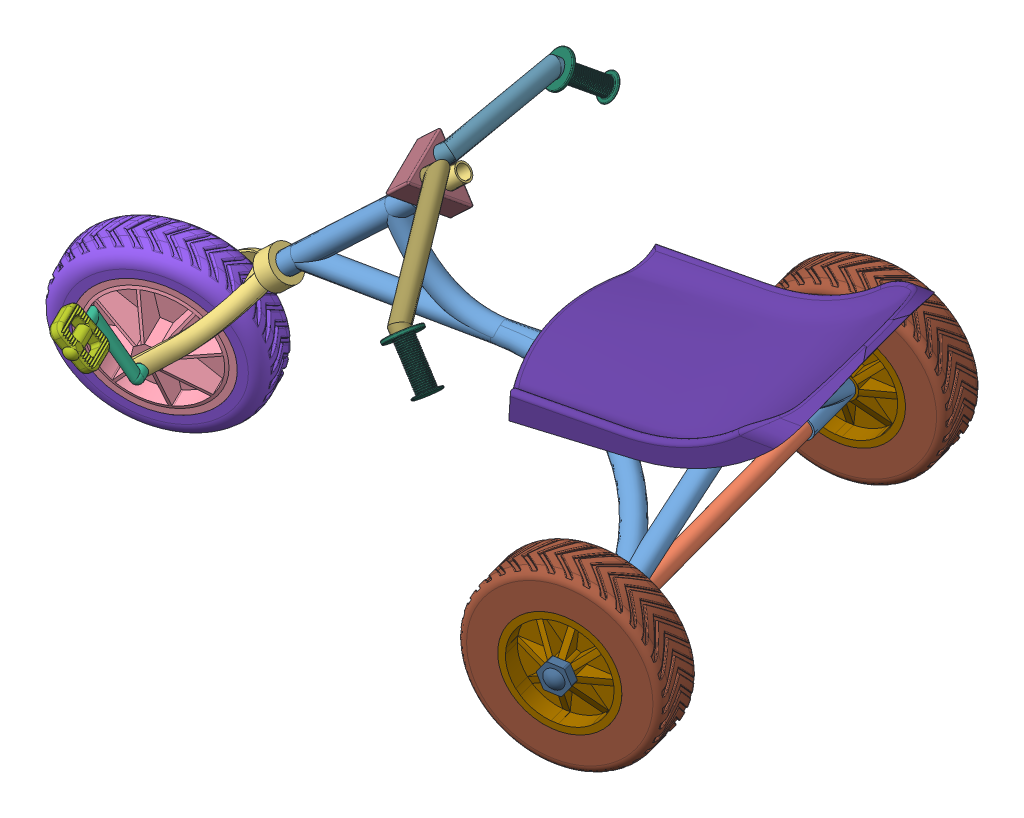
SolidWorks assembly Fiets, configuration Default. Lengths in mm.
Overall size (906.09 547.68 611.83).
25 component instances, 17 part files, 32 mates.
Components (placement in the parent):
- frame-1: frame [Default] at (642.1584 25.2869 3346.6526) x (-0.963262 0.054035 0.263071) z (-0.263456 0 -0.964672) size (454.25 227.22 420.33)
- Achteras-1: Achteras [Default] at (663.0616 75 3631.1981) x (0.960491 -0.092999 -0.262314) z (-0.263456 0 -0.964672) size (20.04 20.01 560.04)
- voorvork+wiel+band-1: voorvork+wiel+band [Default] at (-75.4458 234.9632 3697.8312) x (-0.379608 0.139583 -0.914557) z (0.583431 -0.731077 -0.353745) size (248 508.91 250.19)
  - voorvork-1: voorvork [Default] at (100.9229 178.2623 269.7183) size (130.11 396.12 40)
  - wiel-1: wiel [Default] at (100.9229 44.4443 269.7183) x (0 0.200278 -0.979739) z (1 0 0) size (179.66 179.66 90.02)
  - vooras-1: vooras [Default] at (140.9229 44.4443 269.7183) x (0 -0.74834 -0.663315) z (-1 0 0) size (13.86 12 140)
  - trapper1-3: trapper1 [Default] at (160.9229 44.4443 269.7183) x (0 -0.200278 0.979739) z (0 0.979739 0.200278) size (83 60 14)
  - trapper1-4: trapper1 [Default] at (40.9229 44.4443 269.7183) x (0 0.200278 -0.979739) z (0 0.979739 0.200278) size (83 60 14)
  - trapper2-1: trapper2 [Default] at (20.9229 57.9534 207.1148) x (0 0.085065 -0.996375) z (1 0 0) size (55 15.8 44)
  - trapper2-2: trapper2 [Default] at (180.9229 36.0058 336.0969) x (0 -0.930146 0.36719) z (-1 0 0) size (55 15.8 44)
  - voorband-1: voorband [Default] at (70.9229 44.4443 269.7183) x (0 0.189897 0.981804) z (1 0 0) size (213.53 213.53 60)
- achterwiel-1: achterwiel [Default] at (533.9684 75 3158.509) x (-0.615733 0.769802 0.168159) z (-0.263456 0 -0.964672) size (150 150 60)
- achterwiel-2: achterwiel [Default] at (660.427 75 3621.5514) x (-0.089713 -0.995666 0.024501) z (-0.263456 0 -0.964672) size (150 150 60)
- bout-achteras-1: bout-achteras [Default] at (663.0616 75 3631.1981) x (0.960491 -0.092999 -0.262314) z (-0.263456 0 -0.964672) size (34.02 30 15.01)
- bout-achteras-2: bout-achteras [Default] at (515.5265 75 3090.982) x (-0.960491 0.092999 0.262314) z (0.263456 0 0.964672) size (34.02 30 15.01)
- Achterband-1: Achterband [Default] at (644.6197 75 3563.6711) x (0.960491 -0.092999 -0.262314) z (0.263456 0 0.964672) size (201.31 201.31 60)
- Achterband-2: Achterband [Default] at (518.161 75 3100.6288) x (-0.960491 0.092999 0.262314) z (0.263456 0 0.964672) size (201.31 201.31 60)
- stuur-1: stuur [Default] at (294.7106 365.6419 3434.6157) x (-0.379608 0.139583 -0.914557) z (0.583431 -0.731077 -0.353745) size (435.74 60.06 120.1)
  - stuurbuis1-2: stuurbuis1 [Default] at (-32.5291 -26.394 40.1826) x (-0.965926 0 0.258819) z (-0.258819 0 -0.965926) size (215.96 50 55.96)
  - stuur-tussenstuk-1: stuur-tussenstuk [Default] at (-17.5291 -26.394 90.1345) size (72.07 30.12 62.95)
  - stuurbuis2-1: stuurbuis2 [Default] at (-2.5291 -26.394 40.1826) x (0.965926 0 0.258819) z (-0.258819 0 0.965926) size (215.96 50 55.96)
  - handvat-1: handvat [Default] at (-189.5772 13.606 85.9238) x (-0.5 0 0.866025) z (-0.866025 0 -0.5) size (57 40 40)
  - handvat-2: handvat [Default] at (154.5191 13.606 85.9238) x (0.5 0 0.866025) z (-0.866025 0 0.5) size (57 40 40)
- stuurpen-1: stuurpen [Default] at (319.6176 316.8448 3417.7204) x (0.424318 0.904714 -0.038042) z (0.822102 -0.402505 -0.402664) size (10 33.43 10)
- stoel-1: stoel [Default] at (397.4291 243.1345 3283.9169) x (0.263456 0 0.964672) z (-0.963262 0.054035 0.263071) size (270.97 155.75 335.98)
Mates (geometry in assembly coordinates):
- Coincident2: coincident anti-aligned: circle of frame-1; cylinder of Achteras-1 through (515.5265 75 3090.982) axis (0.263456 0 0.964672) radius 10
- Coincident4: coincident anti-aligned: circle of frame-1; circle of voorvork+wiel+band-1/voorvork-1
- Concentric2: concentric anti-aligned: circle of frame-1; circle of achterwiel-1
- Coincident5: coincident aligned: circle of frame-1; plane of achterwiel-1 through (533.9684 75 3158.509) normal (0.263456 0 0.964672)
- Concentric3: concentric aligned: cylinder of Achteras-1 through (515.5265 75 3090.982) axis (0.263456 0 0.964672) radius 10; cylinder of achterwiel-2 through (652.5234 75 3592.6112) axis (0.263456 0 0.964672) radius 10
- Coincident7: coincident anti-aligned: circle of frame-1; plane of achterwiel-2 through (644.6197 75 3563.6711) normal (-0.263456 0 -0.964672)
- Tangent3: tangent anti-aligned: cylinder of achterwiel-1 through (526.0647 75 3129.5689) axis (0.263456 0 0.964672) radius 75; plane of assembly through (0 0 0) normal (0 1 0)
- Distance1: distance = 70 mm anti-aligned: plane of Achteras-1 through (515.5265 75 3090.982) normal (-0.263456 0 -0.964672); plane of achterwiel-1 through (533.9684 75 3158.509) normal (0.263456 0 0.964672)
- Concentric4: concentric anti-aligned: cylinder of Achteras-1 through (515.5265 75 3090.982) axis (0.263456 0 0.964672) radius 10; circle of bout-achteras-1
- Coincident14: coincident anti-aligned: plane of achterwiel-2 through (660.427 75 3621.5514) normal (0.263456 0 0.964672); plane of bout-achteras-1 through (660.427 75 3621.5514) normal (-0.263456 0 -0.964672)
- Coincident15: coincident aligned: cylinder of Achteras-1 through (515.5265 75 3090.982) axis (0.263456 0 0.964672) radius 10; circle of bout-achteras-2
- Coincident16: coincident anti-aligned: plane of achterwiel-1 through (518.161 75 3100.6288) normal (-0.263456 0 -0.964672); plane of bout-achteras-2 through (518.161 75 3100.6288) normal (0.263456 0 0.964672)
- Parallel1: parallel aligned: plane of achterwiel-2 through (655.4719 78.4848 3602.1722) normal (0.089713 0.995666 -0.024501); plane of Achterband-1
- Parallel2: parallel aligned: plane of achterwiel-1 through (523.1161 71.5152 3120.0079) normal (-0.089713 -0.995666 0.024501); plane of Achterband-2
- Parallel3: parallel aligned: plane of voorvork+wiel+band-1/voorvork-1 through (165.7609 178.2315 3478.7027) normal (-0.583431 0.731077 0.353745); plane of stuur-1/stuur-tussenstuk-1 through (304.4108 352.4274 3406.7358) normal (-0.583431 0.731077 0.353745)
- Concentric8: concentric anti-aligned: cylinder of voorvork+wiel+band-1/voorvork-1 through (351.0922 337.887 3426.1439) axis (-0.717988 -0.667865 0.196085) radius 10; cylinder of stuur-1/stuur-tussenstuk-1 through (315.1928 304.4938 3435.9482) axis (0.717988 0.667865 -0.196085) radius 10
- Concentric10: concentric anti-aligned: cylinder of stuur-1/stuur-tussenstuk-1 through (312.2831 319.5417 3400.05) axis (0.379608 -0.139583 0.914557) radius 5; cylinder of stuurpen-1 through (332.3079 312.1786 3448.2941) axis (-0.379608 0.139583 -0.914557) radius 5
- Tangent4: tangent: curve of stuur-1/stuur-tussenstuk-1; circle of stuurpen-1
- Concentric29: concentric aligned: circle of frame-1; circle of stoel-1
- Concentric30: concentric aligned: circle of frame-1; circle of stoel-1
- Coincident52: coincident aligned: plane of achterwiel-1 through (526.7919 74.6745 3119.0041) normal (0.960491 -0.092999 -0.262314); plane of achterwiel-2 through (653.2505 74.6745 3582.0464) normal (0.960491 -0.092999 -0.262314)
- Coincident55: coincident: line of achterwiel-2 through (726.82 52.532 3593.053) axis (-0.263456 0 -0.964672); cylinder of Achterband-1 through (647.2543 75 3573.3178) axis (0.263456 0 0.964672) radius 75
- Coincident56: coincident anti-aligned: plane of achterwiel-2 through (647.2543 75 3573.3178) normal (-0.263456 0 -0.964672); plane of Achterband-1 through (647.2543 75 3573.3178) normal (0.263456 0 0.964672)
- Concentric31: concentric aligned: cylinder of achterwiel-2 through (652.5234 75 3592.6112) axis (0.263456 0 0.964672) radius 75; cylinder of Achterband-1 through (647.2543 75 3573.3178) axis (0.263456 0 0.964672) radius 75
- Coincident57: coincident anti-aligned: plane of achterwiel-1 through (520.7956 75 3110.2755) normal (-0.263456 0 -0.964672); plane of Achterband-2 through (520.7956 75 3110.2755) normal (0.263456 0 0.964672)
- Concentric32: concentric aligned: cylinder of achterwiel-1 through (526.0647 75 3129.5689) axis (0.263456 0 0.964672) radius 75; cylinder of Achterband-2 through (520.7956 75 3110.2755) axis (0.263456 0 0.964672) radius 75
- Parallel4: parallel aligned: plane of Achteras-1; plane of achterwiel-1 through (523.1161 71.5152 3120.0079) normal (-0.089713 -0.995666 0.024501)
- Coincident60: coincident anti-aligned: plane of frame-1 through (650.6868 188.6572 3344.3235) normal (0.052126 0.998539 -0.014236); plane of stoel-1 through (540.1665 194.5319 3351.7069) normal (-0.052126 -0.998539 0.014236)
- Concentric33: concentric aligned: cylinder of voorvork+wiel+band-1/voorvork-1 through (348.7645 306.1274 3487.9417) axis (-0.379608 0.139583 -0.914557) radius 5; cylinder of stuurpen-1 through (332.3079 312.1786 3448.2941) axis (-0.379608 0.139583 -0.914557) radius 5
- Coincident61: coincident aligned: plane of Achteras-1; plane of bout-achteras-2
- Coincident62: coincident aligned: plane of Achteras-1; plane of bout-achteras-1
- LimitAngle1: limit planar angle = 0.188657 rad aligned: plane of stuur-1/stuur-tussenstuk-1; plane of frame-1 through (642.1584 25.2869 3346.6526) normal (-0.263456 0 -0.964672)
